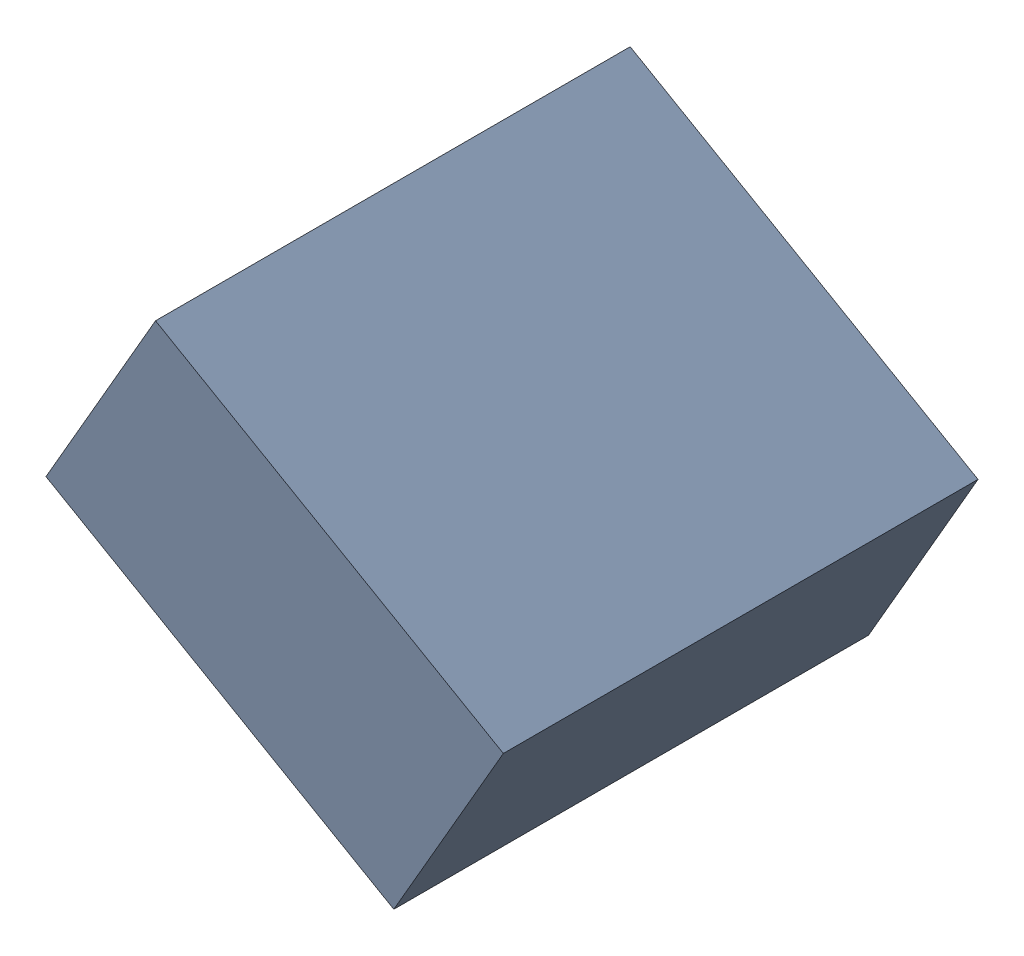
SolidWorks assembly C27_TDA6, configuration Standard. Lengths in mm.
Overall size (1.25 1.07 1.3).
2 component instances, 1 part files, 0 mates.
Components (placement in the parent):
- 885543056-1: 885543056 [Standard] at (-47.9541 32.1333 0) size (1.25 1.07 1.3)
  - Extruded_23-1: Extruded_23 [Standard] at origin size (1.25 1.07 1.3)
